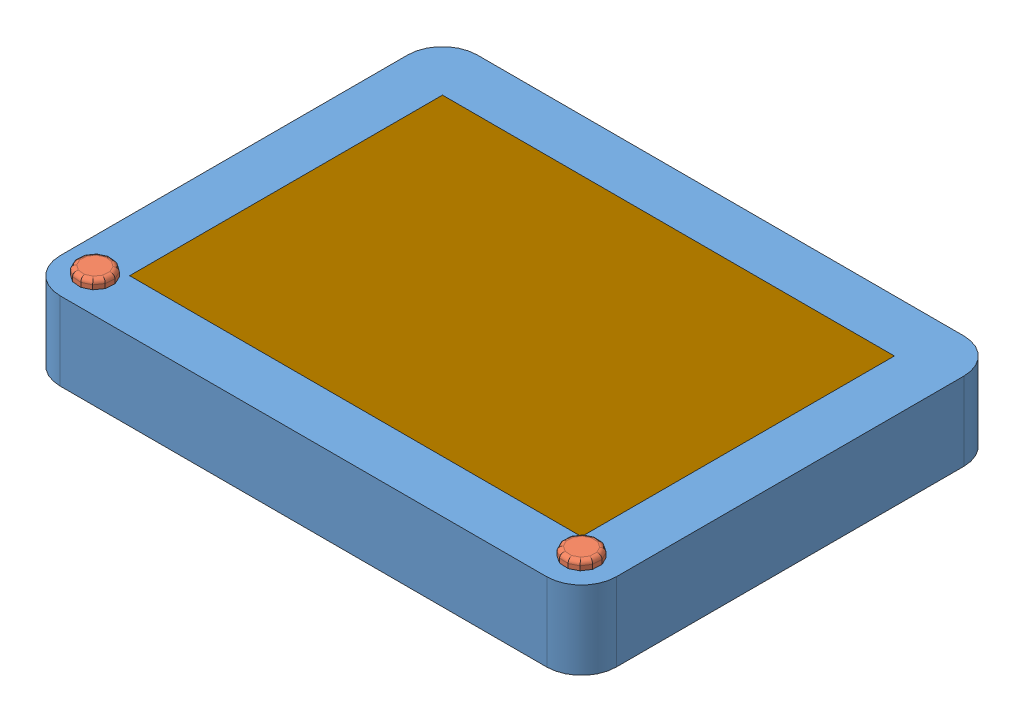
SolidWorks assembly Etch-a-Sketch, configuration Default. Lengths in mm.
Overall size (203.2 31.75 152.4).
25 component instances, 9 part files, 47 mates.
Components (placement in the parent):
- etch_body-1: etch_body [Default] at (90.2745 93.198 157.0866) size (203.2 28.57 152.4)
- etch_dial-1: etch_dial [Default] at (179.1745 123.3605 220.5866) x (0.978514 0 -0.206179) z (0.206179 0 0.978514) size (17.78 29.37 17.78)
- etch_dial-2: etch_dial [Default] at (1.3745 123.3605 220.5866) x (-0.64278 0 -0.76605) z (0.76605 0 -0.64278) size (17.78 29.37 17.78)
- etch_gear-1: etch_gear [Default] at (1.3745 93.9917 202.4437) x (0.738869 0 0.673849) z (-0.673849 0 0.738869) size (17.78 23.81 17.78)
- etch_gear-2: etch_gear [Default] at (1.3745 93.9917 129.8723) x (0.751354 0 -0.6599) z (0.6599 0 0.751354) size (17.78 23.81 17.78)
- etch_gear-3: etch_gear [Default] at (1.3745 93.9917 184.3009) x (0.751354 0 -0.6599) z (0.6599 0 0.751354) size (17.78 23.81 17.78)
- etch_gear-4: etch_gear [Default] at (1.3745 93.9917 93.5866) x (0.751354 0 -0.6599) z (0.6599 0 0.751354) size (17.78 23.81 17.78)
- etch_gear-5: etch_gear [Default] at (1.3745 93.9917 111.7294) x (0.751354 0 -0.6599) z (0.6599 0 0.751354) size (17.78 23.81 17.78)
- etch_gear-6: etch_gear [Default] at (1.3745 93.9917 148.0151) x (0.751354 0 -0.6599) z (0.6599 0 0.751354) size (17.78 23.81 17.78)
- etch_gear-7: etch_gear [Default] at (1.3745 93.9917 166.158) x (0.751354 0 -0.6599) z (0.6599 0 0.751354) size (17.78 23.81 17.78)
- etch_gear-8: etch_gear [Default] at (36.9345 93.9917 220.5866) x (-0.91207 0 -0.410035) z (0.410035 0 -0.91207) size (17.78 23.81 17.78)
- etch_gear-9: etch_gear [Default] at (19.1545 93.9917 220.5866) x (-0.91207 0 -0.410035) z (0.410035 0 -0.91207) size (17.78 23.81 17.78)
- etch_gear-10: etch_gear [Default] at (125.8345 93.9917 220.5866) x (-0.929628 0 0.368499) z (-0.368499 0 -0.929628) size (17.78 23.81 17.78)
- etch_gear-11: etch_gear [Default] at (108.0545 93.9917 220.5866) x (-0.929628 0 0.368499) z (-0.368499 0 -0.929628) size (17.78 23.81 17.78)
- etch_gear-12: etch_gear [Default] at (143.6145 93.9917 220.5866) x (-0.929628 0 0.368499) z (-0.368499 0 -0.929628) size (17.78 23.81 17.78)
- etch_gear-13: etch_gear [Default] at (161.3945 93.9917 220.5866) x (-0.929628 0 0.368499) z (-0.368499 0 -0.929628) size (17.78 23.81 17.78)
- etch_gear-14: etch_gear [Default] at (90.2745 93.9917 220.5866) x (-0.91207 0 -0.410035) z (0.410035 0 -0.91207) size (17.78 23.81 17.78)
- etch_gear-15: etch_gear [Default] at (72.4945 93.9917 220.5866) x (-0.91207 0 -0.410035) z (0.410035 0 -0.91207) size (17.78 23.81 17.78)
- etch_gear-16: etch_gear [Default] at (54.7145 93.9917 220.5866) x (-0.91207 0 -0.410035) z (0.410035 0 -0.91207) size (17.78 23.81 17.78)
- etch_belt_1-1: etch_belt_1 [Default] at (1.3745 98.7542 157.0866) x (0 0 -1) z (1 0 0) size (139.7 1.59 12.7)
- etch_belt_2-1: etch_belt_2 [Default] at (99.1645 98.7542 220.5866) size (172.72 1.59 12.7)
- etch_slider_long-1: etch_slider_long [Default] at (99.4026 106.6917 157.43) size (181.77 1.98 19.05)
- etch_slider_short-1: etch_slider_short [Default] at (93.311 108.6761 147.9584) x (0 0 -1) z (1 0 0) size (130.97 1.98 19.05)
- etch_stylus-1: etch_stylus [Default] at (93.311 93.198 157.43) x (-0.999264 0 -0.038352) z (0.038352 0 -0.999264) size (3.17 23.81 3.17)
- etch_screen-1: etch_screen [Default] at (90.2745 120.1855 157.0866) size (165.1 1.59 114.3)
Mates (geometry in assembly coordinates):
- Coincident3: coincident: circle of etch_body-1; circle of etch_dial-1
- Coincident6: coincident anti-aligned: circle of etch_body-1; circle of etch_dial-2
- Coincident9: coincident anti-aligned: circle of etch_body-1; circle of etch_gear-1
- Coincident10: coincident anti-aligned: circle of etch_body-1; circle of etch_gear-3
- Coincident11: coincident anti-aligned: circle of etch_body-1; circle of etch_gear-6
- Coincident12: coincident anti-aligned: circle of etch_body-1; circle of etch_gear-2
- Coincident13: coincident anti-aligned: circle of etch_body-1; circle of etch_gear-5
- Coincident14: coincident anti-aligned: circle of etch_body-1; circle of etch_gear-4
- Coincident15: coincident anti-aligned: circle of etch_body-1; circle of etch_gear-7
- GearMate1: gear = 9.525 : 9.525 mm: cylinder of etch_dial-2 through (1.3745 98.7542 220.5866) axis (0 1 0) radius 4.7625; cylinder of etch_gear-1 through (1.3745 100.3417 202.4437) axis (0 -1 0) radius 4.7625
- GearMate2: gear = 9.525 : 9.525 mm: cylinder of etch_gear-1 through (1.3745 100.3417 202.4437) axis (0 -1 0) radius 4.7625; cylinder of etch_gear-3 through (1.3745 100.3417 184.3009) axis (0 -1 0) radius 4.7625
- GearMate3: gear = 9.525 : 9.525 mm: cylinder of etch_gear-3 through (1.3745 100.3417 184.3009) axis (0 -1 0) radius 4.7625; cylinder of etch_gear-7 through (1.3745 100.3417 166.158) axis (0 -1 0) radius 4.7625
- GearMate4: gear = 9.525 : 9.525 mm: cylinder of etch_gear-7 through (1.3745 100.3417 166.158) axis (0 -1 0) radius 4.7625; cylinder of etch_gear-6 through (1.3745 100.3417 148.0151) axis (0 -1 0) radius 4.7625
- GearMate5: gear = 9.525 : 9.525 mm: cylinder of etch_gear-6 through (1.3745 100.3417 148.0151) axis (0 -1 0) radius 4.7625; cylinder of etch_gear-2 through (1.3745 100.3417 129.8723) axis (0 -1 0) radius 4.7625
- GearMate6: gear = 9.525 : 9.525 mm: cylinder of etch_gear-2 through (1.3745 100.3417 129.8723) axis (0 -1 0) radius 4.7625; cylinder of etch_gear-5 through (1.3745 100.3417 111.7294) axis (0 -1 0) radius 4.7625
- GearMate7: gear = 9.525 : 9.525 mm: cylinder of etch_gear-5 through (1.3745 100.3417 111.7294) axis (0 -1 0) radius 4.7625; cylinder of etch_gear-4 through (1.3745 100.3417 93.5866) axis (0 -1 0) radius 4.7625
- Coincident16: coincident: circle of etch_body-1; circle of etch_gear-13
- Coincident17: coincident: circle of etch_body-1; circle of etch_gear-12
- Coincident18: coincident: circle of etch_body-1; circle of etch_gear-10
- Coincident19: coincident: circle of etch_body-1; circle of etch_gear-11
- Coincident20: coincident: circle of etch_body-1; circle of etch_gear-14
- Coincident21: coincident: circle of etch_body-1; circle of etch_gear-15
- Coincident22: coincident: circle of etch_body-1; circle of etch_gear-16
- Coincident23: coincident: circle of etch_body-1; circle of etch_gear-8
- Coincident24: coincident: circle of etch_body-1; circle of etch_gear-9
- GearMate8: gear = 9.525 : 9.525 mm: cylinder of etch_gear-9 through (19.1545 100.3417 220.5866) axis (0 -1 0) radius 4.7625; cylinder of etch_gear-8 through (36.9345 100.3417 220.5866) axis (0 -1 0) radius 4.7625
- GearMate9: gear = 9.525 : 9.525 mm: cylinder of etch_gear-8 through (36.9345 100.3417 220.5866) axis (0 -1 0) radius 4.7625; cylinder of etch_gear-16 through (54.7145 100.3417 220.5866) axis (0 -1 0) radius 4.7625
- GearMate10: gear = 9.525 : 9.525 mm: cylinder of etch_gear-16 through (54.7145 100.3417 220.5866) axis (0 -1 0) radius 4.7625; cylinder of etch_gear-15 through (72.4945 100.3417 220.5866) axis (0 -1 0) radius 4.7625
- GearMate11: gear = 9.525 : 9.525 mm: cylinder of etch_gear-15 through (72.4945 100.3417 220.5866) axis (0 -1 0) radius 4.7625; cylinder of etch_gear-14 through (90.2745 100.3417 220.5866) axis (0 -1 0) radius 4.7625
- GearMate12: gear = 9.525 : 9.525 mm: cylinder of etch_gear-11 through (108.0545 100.3417 220.5866) axis (0 -1 0) radius 4.7625; cylinder of etch_gear-10 through (125.8345 100.3417 220.5866) axis (0 -1 0) radius 4.7625
- GearMate13: gear = 9.525 : 9.525 mm: cylinder of etch_gear-10 through (125.8345 100.3417 220.5866) axis (0 -1 0) radius 4.7625; cylinder of etch_gear-12 through (143.6145 100.3417 220.5866) axis (0 -1 0) radius 4.7625
- GearMate14: gear = 9.525 : 9.525 mm: cylinder of etch_gear-12 through (143.6145 100.3417 220.5866) axis (0 -1 0) radius 4.7625; cylinder of etch_gear-13 through (161.3945 100.3417 220.5866) axis (0 -1 0) radius 4.7625
- GearMate15: gear = 9.525 : 9.525 mm: cylinder of etch_gear-13 through (161.3945 100.3417 220.5866) axis (0 -1 0) radius 4.7625; cylinder of etch_dial-1 through (179.1745 98.7542 220.5866) axis (0 1 0) radius 4.7625
- Coincident25: coincident anti-aligned: circle of etch_dial-2; circle of etch_belt_1-1
- Coincident28: coincident: circle of etch_dial-1; circle of etch_belt_2-1
- Coincident29: coincident: circle of etch_gear-9; circle of etch_belt_2-1
- Coincident30: coincident aligned: circle of etch_gear-4; circle of etch_belt_1-1
- Coincident31: coincident anti-aligned: plane of etch_gear-3 through (1.3745 106.6917 184.3009) normal (0 1 0); plane of etch_slider_long-1 through (99.4026 106.6917 157.43) normal (0 -1 0)
- Tangent1: tangent anti-aligned: cylinder of etch_gear-7 through (1.3745 117.8042 166.158) axis (0 -1 0) radius 6.35; plane of etch_slider_long-1 through (7.7245 108.6761 157.43) normal (-1 0 0)
- Coincident33: coincident anti-aligned: plane of etch_slider_long-1 through (99.4026 108.6761 157.43) normal (0 1 0); plane of etch_slider_short-1 through (93.311 108.6761 147.9584) normal (0 -1 0)
- RackPinionMate2: rack pinion = 12.7 mm: line of etch_slider_short-1 through (109.186 110.6605 214.2366) axis (-1 0 0); circle of etch_gear-15
- GearMate16: gear = 9.525 : 9.525 mm: cylinder of etch_gear-11 through (108.0545 100.3417 220.5866) axis (0 -1 0) radius 4.7625; cylinder of etch_gear-14 through (90.2745 100.3417 220.5866) axis (0 -1 0) radius 4.7625
- Tangent4: tangent anti-aligned: plane of etch_slider_short-1 through (91.7235 110.6605 147.9584) normal (1 0 0); cylinder of etch_stylus-1 through (93.311 110.6605 157.43) axis (0 -1 0) radius 1.5875
- Tangent5: tangent anti-aligned: plane of etch_slider_long-1 through (99.4026 108.6761 155.8425) normal (0 0 1); cylinder of etch_stylus-1 through (93.311 110.6605 157.43) axis (0 -1 0) radius 1.5875
- Coincident37: coincident anti-aligned: plane of etch_body-1 through (179.1745 93.198 220.5866) normal (0 1 0); plane of etch_stylus-1 through (93.311 93.198 157.43) normal (0 -1 0)
- Coincident38: coincident aligned: line of etch_body-1 through (7.7245 120.1855 214.2366) axis (1 0 0); line of etch_screen-1 through (7.7245 120.1855 214.2366) axis (1 0 0)
- Coincident39: coincident aligned: line of etch_body-1 through (7.7245 120.1855 99.9366) axis (0 0 1); line of etch_screen-1 through (7.7245 120.1855 99.9366) axis (0 0 1)
